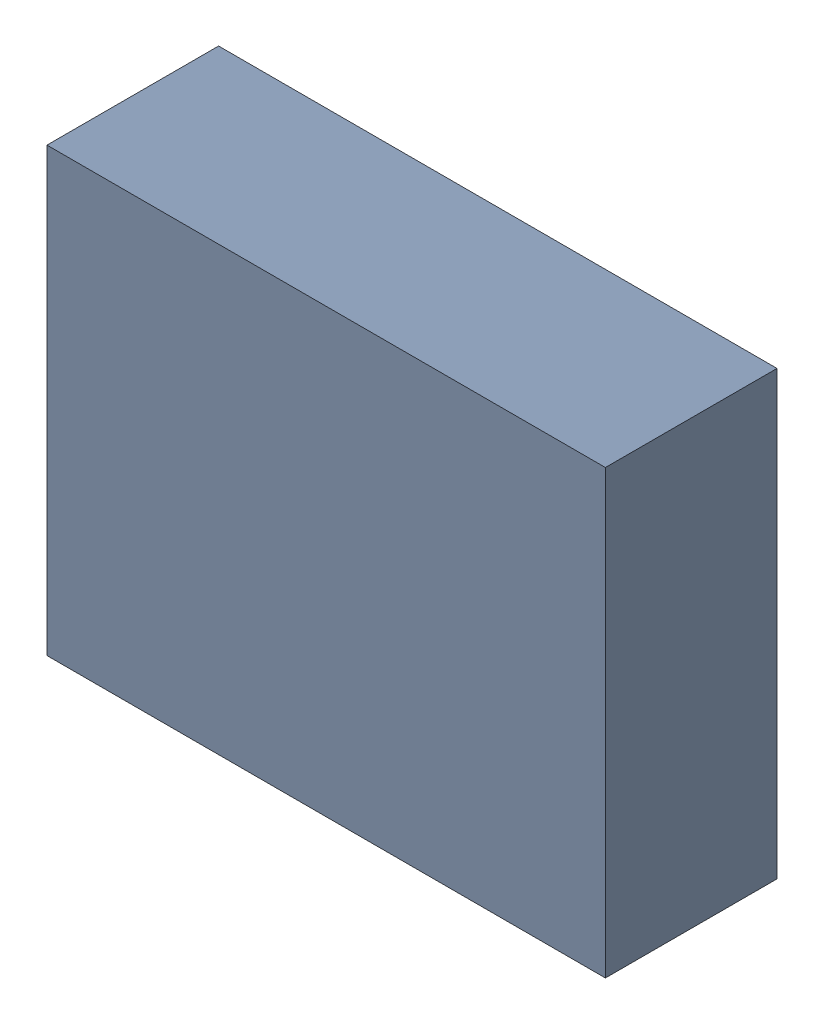
SolidWorks assembly OP2, configuration Default. Lengths in mm.
Overall size (5.04 3.99 1.55).
2 component instances, 1 part files, 0 mates.
Components (placement in the parent):
- 407985952-1: 407985952 [Default] at (55.372 46.863 0.2157) size (5.04 3.99 1.55)
  - Extruded-1: Extruded [Default] at origin size (5.04 3.99 1.55)
